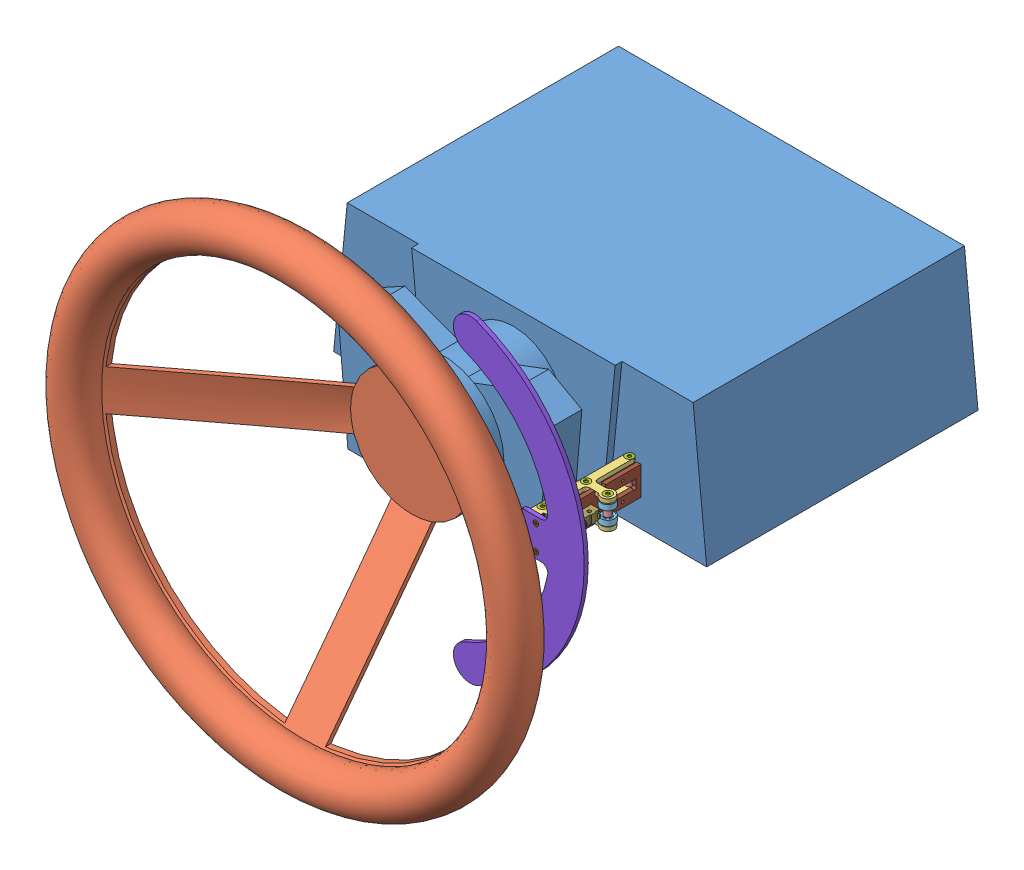
SolidWorks assembly steering assembly, configuration Default. Lengths in mm.
Overall size (355 355 381).
31 component instances, 12 part files, 5 mates.
Components (placement in the parent):
- base-1: base [Default] at origin size (275 100 276)
- wheel-1: wheel [Default] at (0 0 76) x (1 0 0) z (0 -1 0) size (355 105 355)
- shifter assembly-1: shifter assembly [Default] at (114.2407 -10.9539 49.6927) x (0 0 1) z (-1 0 0) size (79 234.52 96.49)
  - arm-1: arm [Bottom] at origin size (77.3 3 23.76)
  - arm-2: arm [Top] at (0 18 0) size (77.3 3 23.76)
  - standoff-15mm-1: standoff-15mm [Default] at (-32 3 16) x (0.079826 0 0.996809) z (-0.996809 0 0.079826) size (5 15 5)
  - standoff-15mm-2: standoff-15mm [Default] at (0 3 16) x (0.266249 0 0.963904) z (-0.963904 0 0.266249) size (5 15 5)
  - standoff-15mm-3: standoff-15mm [Default] at (32 3 16) x (0.46778 0 0.883845) z (-0.883845 0 0.46778) size (5 15 5)
  - standoff-15mm-4: standoff-15mm [Default] at (38 3 2) x (0.661946 0 0.749552) z (-0.749552 0 0.661946) size (5 15 5)
  - bearing-5x10x4-1: bearing-5x10x4 [Default] at (0 13.5 0) x (0.999569 0 0.029351) z (-0.029351 0 0.999569) size (10 4 10)
  - bearing-spacer-1: bearing-spacer [Default] at (0 17.5 0) size (7.5 0.5 7.5)
  - bearing-5x10x4-2: bearing-5x10x4 [Default] at (0 3.5 0) x (0.625763 0 0.780013) z (-0.780013 0 0.625763) size (10 4 10)
  - bearing-spacer-2: bearing-spacer [Default] at (0 3 0) size (7.5 0.5 7.5)
  - countersunk-screw-m3-8mm-1: countersunk-screw-m3-8mm [Default] at (-32 20.9995 16) x (0 -1 0) z (0 0 1) size (8 6 6)
  - countersunk-screw-m3-8mm-2: countersunk-screw-m3-8mm [Default] at (0 20.9995 16) x (0 -1 0) z (0.188455 0 0.982082) size (8 6 6)
  - countersunk-screw-m3-8mm-4: countersunk-screw-m3-8mm [Default] at (32 20.9995 16) x (0 -1 0) z (0.395734 0 0.918365) size (8 6 6)
  - countersunk-screw-m3-8mm-6: countersunk-screw-m3-8mm [Default] at (38 20.9995 2) x (0 -1 0) z (0.6 0 0.8) size (8 6 6)
  - countersunk-screw-m3-8mm-8: countersunk-screw-m3-8mm [Default] at (-32 0.0005 16) x (0 1 0) z (1 0 0) size (8 6 6)
  - countersunk-screw-m3-8mm-10: countersunk-screw-m3-8mm [Default] at (0 0.0005 16) x (0 1 0) z (1 0 0) size (8 6 6)
  - countersunk-screw-m3-8mm-12: countersunk-screw-m3-8mm [Default] at (32 0.0005 16) x (0 1 0) z (1 0 0) size (8 6 6)
  - countersunk-screw-m3-8mm-14: countersunk-screw-m3-8mm [Default] at (38 0.0005 2) x (0 1 0) z (1 0 0) size (8 6 6)
  - paddle-1: paddle [Default] at (41 10.5 98.3366) x (0 0 -1) z (0 -1 0) size (96.49 3 234.52)
  - countersunk-screw-m2-8mm-1: countersunk-screw-m2-8mm [Default] at (43.9 19.5 9) x (-1 0 0) z (0 0 -1) size (8 4 4)
  - countersunk-screw-m2-8mm-2: countersunk-screw-m2-8mm [Default] at (43.9 1.5 9) x (-1 0 0) z (0 0.158553 -0.987351) size (8 4 4)
  - nut-m2-1: nut-m2 [Default] at (36 19.5 9) x (0 1 0) z (1 0 0) size (4.62 4 2)
  - nut-m2-2: nut-m2 [Default] at (36 1.5 9) x (0 1 0) z (1 0 0) size (4.62 4 2)
  - body-1: body [Default] at (-0.9411 10.5 6.4486) x (1 0 0) z (0 -1 0) size (60 3 21)
  - switch-1: switch [Default] at (15.5589 10.5 5.0986) x (1 0 0) z (0 0 -1) size (28.06 6.35 15.08)
  - standoff-15mm-5: standoff-15mm [Default] at (0 3 0) x (0.892707 0 0.450638) z (-0.450638 0 0.892707) size (5 15 5)
  - countersunk-screw-m3-8mm-16: countersunk-screw-m3-8mm [Default] at (0 20.9995 0) x (0 -1 0) z (0.370156 0 0.92897) size (8 6 6)
  - countersunk-screw-m3-8mm-18: countersunk-screw-m3-8mm [Default] at (0 0.0005 0) x (0 1 0) z (0.982082 0 0.188455) size (8 6 6)
Mates (geometry in assembly coordinates):
- Coincident1: coincident: plane of base-1 through (0 0 76) normal (0 0 1); plane of wheel-1 through (0 0 76) normal (0 0 -1)
- Concentric1: concentric: cylinder of base-1 through (0 0 76) axis (0 0 -1) radius 45; cylinder of wheel-1 through (0 0 75.999) axis (0 0 1) radius 45
- Concentric2: concentric: cylinder of base-1 through (0 0 76) axis (0 0 -1) radius 45; cylinder of ? through (0 0 96) axis (0 0 -1) radius 125
- Distance1: distance = 70 mm: plane of wheel-1 through (0 0 166) normal (0 0 1); plane of ? through (0 0 96) normal (0 0 1)
- Coincident3: coincident: plane of ? through (0 0 93) normal (0 -1 0); plane of assembly through (0 0 0) normal (0 1 0)
